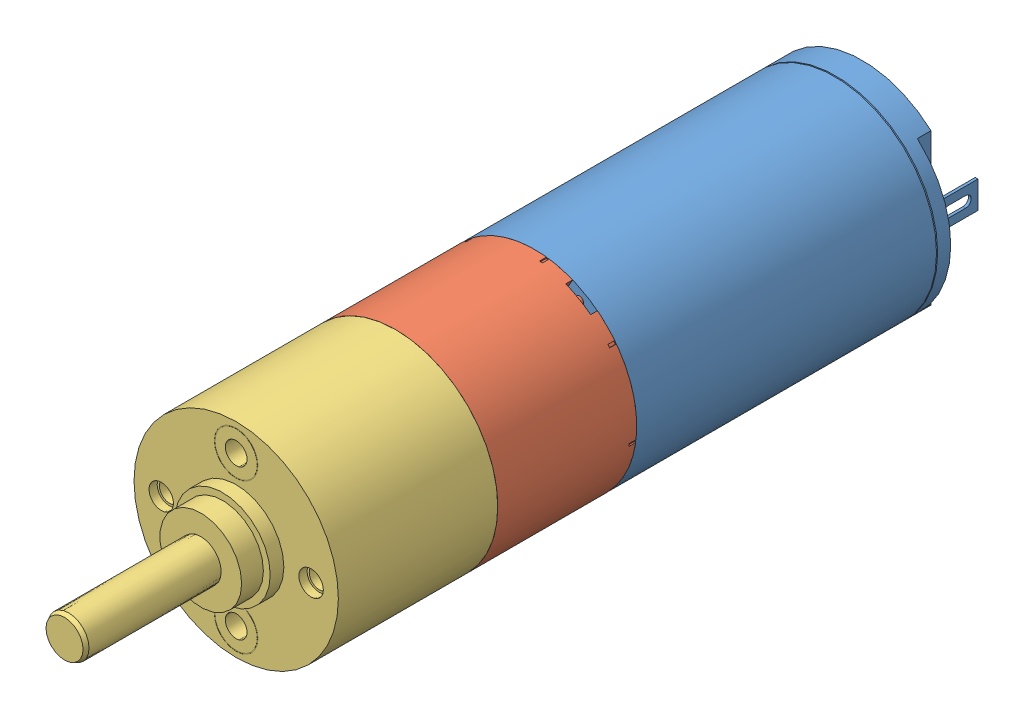
SolidWorks assembly Motor, configuration Standard. Lengths in mm.
Overall size (20.48 20.48 61.75).
3 component instances, 3 part files, 2 mates.
Components (placement in the parent):
- 1524T_SR-1: 1524T_SR [Standard] at (-5.843 -0.6961 22.25) size (15 15 36.1)
- 15A_flange_a.stp-1: 15A_flange_a.stp [Standard] at (-5.843 -0.6961 45.3) x (0.866519 -0.499144 0) z (0 0 1) size (15 15 10.8)
- 15A_3stage-1: 15A_3stage [Standard] at (-5.843 -0.6961 67.2) size (15 15 32)
Mates (geometry in assembly coordinates):
- Deckungsgleich7: coincident aligned: circle of 1524T_SR-1; circle of 15A_flange_a.stp-1
- Deckungsgleich10: coincident aligned: circle of 15A_flange_a.stp-1; circle of 15A_3stage-1
